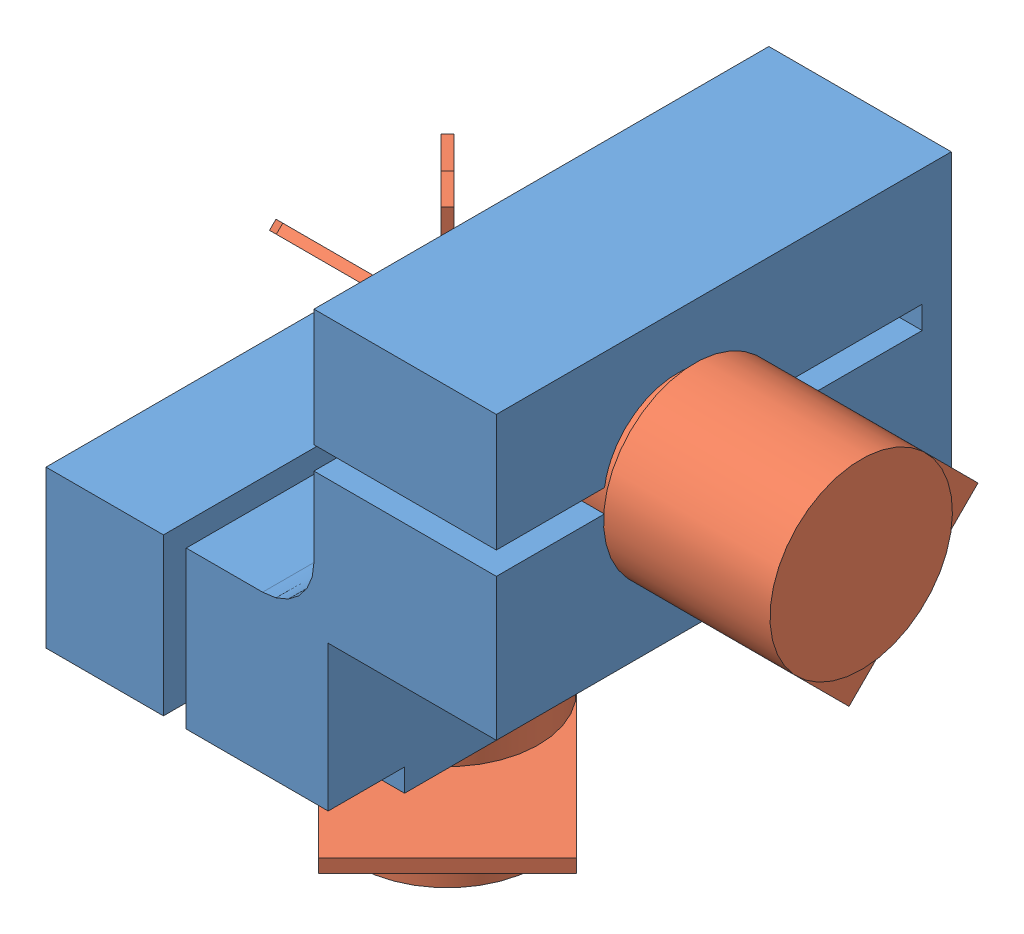
SolidWorks assembly galvo_assm, configuration Default. Lengths in mm.
Overall size (55.61 56.36 39.9).
3 component instances, 2 part files, 7 mates.
Components (placement in the parent):
- galvo_holder-1: galvo_holder [Default] at origin size (39.5 39.5 39.9)
- galvo-1: galvo [Default] at (11.3 -8.85 16) x (-0.707107 0 -0.707107) z (0 -1 0) size (25.8 16 50.2)
- galvo-2: galvo [Default] at (47.6 28.2 24) x (0 0.707107 0.707107) z (1 0 0) size (25.8 16 50.2)
Mates (geometry in assembly coordinates):
- Coincident1: coordinate: point of galvo_holder-1
- Concentric1: concentric: cylinder of galvo_holder-1 through (0 28.2 24) axis (1 0 0) radius 6.5; cylinder of galvo-2 through (55.6 28.2 24) axis (1 0 0) radius 6.5
- Concentric2: concentric aligned: cylinder of galvo_holder-1 through (11.3 39.5 16) axis (0 -1 0) radius 6.5; cylinder of galvo-1 through (11.3 -16.85 16) axis (0 -1 0) radius 6.5
- Angle1: planar angle = 0.785398 rad aligned: plane of galvo_holder-1 through (0 0 39.9) normal (-1 0 0); plane of galvo-1 through (5.6431 -7.65 21.6569) normal (-0.707107 0 0.707107)
- Distance2: distance = 3 mm aligned: plane of galvo_holder-1 through (0 15.75 39.9) normal (0 1 0); plane of galvo-1 through (15.0123 18.75 19.7123) normal (0 1 0)
- Distance3: distance = 3.5 mm: plane of galvo-2 through (20 24.4877 20.2877) normal (-1 0 0); plane of galvo_holder-1 through (23.5 20.25 39.9) normal (-1 0 0)
- Angle2: planar angle = 0.785398 rad aligned: plane of galvo-2 through (46.4 33.8569 18.3431) normal (0 0.707107 -0.707107); plane of galvo_holder-1 through (23.5 39.5 39.9) normal (0 1 0)
